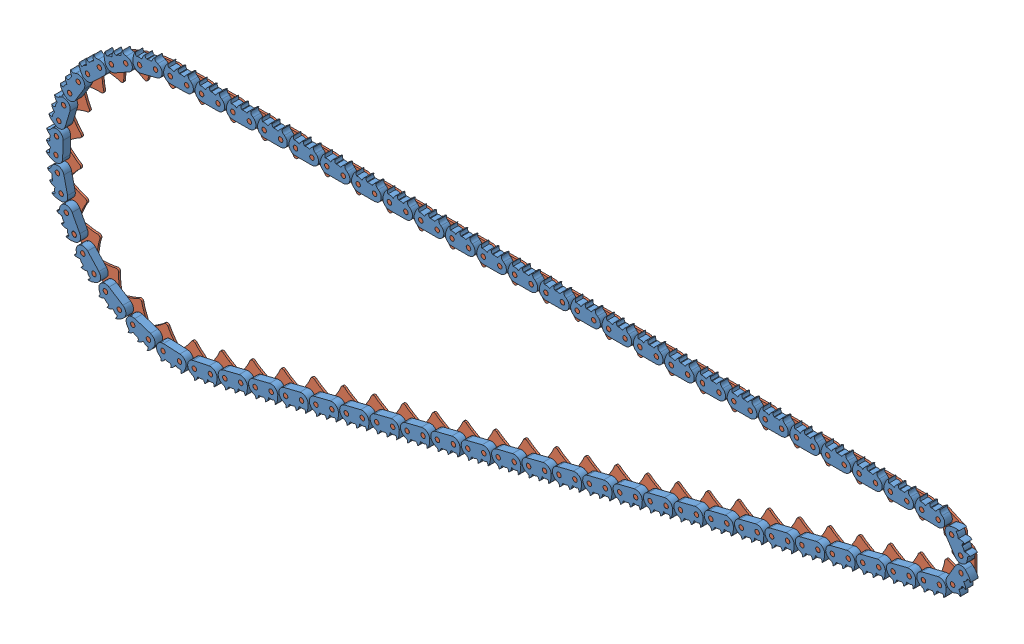
SolidWorks assembly Assem3, configuration Default. Lengths in mm.
Overall size (244.15 69.29 2.5).
128 component instances, 2 part files, 3 mates.
Components (placement in the parent):
- Teeth-4: Teeth [Default] at (-150.1835 11.9639 717.1655) x (0.465892 -0.884842 0) z (0 0 -1) size (7.83 4.36 2)
- Inner Part-4: Inner Part [Default] at (-149.4974 11.0464 714.6655) x (-0.348131 0.937446 0) z (0 0 1) size (7.41 6.1 2.5)
- Teeth-198: Teeth [Default] at (-151.9113 20.0795 717.1655) x (0.224544 -0.974464 0) z (0 0 -1) size (7.83 4.36 2)
- Teeth-199: Teeth [Default] at (-151.5087 28.3672 717.1655) x (-0.031796 -0.999494 0) z (0 0 -1) size (7.83 4.36 2)
- Teeth-200: Teeth [Default] at (-149.0024 36.2772 717.1655) x (-0.286063 -0.958211 0) z (0 0 -1) size (7.83 4.36 2)
- Teeth-201: Teeth [Default] at (-144.5589 43.2847 717.1655) x (-0.52131 -0.853367 0) z (0 0 -1) size (7.83 4.36 2)
- Teeth-202: Teeth [Default] at (-138.4738 48.9255 717.1655) x (-0.721899 -0.691999 0) z (0 0 -1) size (7.83 4.36 2)
- Teeth-203: Teeth [Default] at (-131.1508 52.827 717.1655) x (-0.874568 -0.484903 0) z (0 0 -1) size (7.83 4.36 2)
- Teeth-204: Teeth [Default] at (-123.0752 54.7323 717.1655) x (-0.969306 -0.245857 0) z (0 0 -1) size (7.83 4.36 2)
- Teeth-205: Teeth [Default] at (-114.7809 54.6665 717.1655) x (-0.999921 -0.012594 0) z (0 0 -1) size (7.83 4.36 2)
- Teeth-206: Teeth [Default] at (-106.5352 54.6348 717.1655) x (-1 0 0) z (0 0 -1) size (7.83 4.36 2)
- Teeth-207: Teeth [Default] at (-98.2897 54.6348 717.1655) x (-1 0 0) z (0 0 -1) size (7.83 4.36 2)
- Teeth-208: Teeth [Default] at (-90.0442 54.6348 717.1655) x (-1 0 0) z (0 0 -1) size (7.83 4.36 2)
- Teeth-209: Teeth [Default] at (-81.7987 54.6348 717.1655) x (-1 0 0) z (0 0 -1) size (7.83 4.36 2)
- Teeth-210: Teeth [Default] at (-73.5532 54.6348 717.1655) x (-1 0 0) z (0 0 -1) size (7.83 4.36 2)
- Teeth-211: Teeth [Default] at (-65.3077 54.6348 717.1655) x (-1 0 0) z (0 0 -1) size (7.83 4.36 2)
- Teeth-212: Teeth [Default] at (-57.0622 54.6348 717.1655) x (-1 0 0) z (0 0 -1) size (7.83 4.36 2)
- Teeth-213: Teeth [Default] at (-48.8167 54.6348 717.1655) x (-1 0 0) z (0 0 -1) size (7.83 4.36 2)
- Teeth-214: Teeth [Default] at (-40.5712 54.6348 717.1655) x (-1 0 0) z (0 0 -1) size (7.83 4.36 2)
- Teeth-215: Teeth [Default] at (-32.3257 54.6348 717.1655) x (-1 0 0) z (0 0 -1) size (7.83 4.36 2)
- Teeth-216: Teeth [Default] at (-24.0802 54.6348 717.1655) x (-1 0 0) z (0 0 -1) size (7.83 4.36 2)
- Teeth-217: Teeth [Default] at (-15.8347 54.6348 717.1655) x (-1 0 0) z (0 0 -1) size (7.83 4.36 2)
- Teeth-218: Teeth [Default] at (-7.5892 54.6348 717.1655) x (-1 0 0) z (0 0 -1) size (7.83 4.36 2)
- Teeth-219: Teeth [Default] at (0.6563 54.6348 717.1655) x (-1 0 0) z (0 0 -1) size (7.83 4.36 2)
- Teeth-220: Teeth [Default] at (8.9018 54.6348 717.1655) x (-1 0 0) z (0 0 -1) size (7.83 4.36 2)
- Teeth-221: Teeth [Default] at (17.1473 54.6348 717.1655) x (-1 0 0) z (0 0 -1) size (7.83 4.36 2)
- Teeth-222: Teeth [Default] at (25.3927 54.6348 717.1655) x (-1 0 0) z (0 0 -1) size (7.83 4.36 2)
- Teeth-223: Teeth [Default] at (33.6382 54.6348 717.1655) x (-1 0 0) z (0 0 -1) size (7.83 4.36 2)
- Teeth-224: Teeth [Default] at (41.8837 54.6348 717.1655) x (-1 0 0) z (0 0 -1) size (7.83 4.36 2)
- Teeth-225: Teeth [Default] at (50.1292 54.6348 717.1655) x (-1 0 0) z (0 0 -1) size (7.83 4.36 2)
- Teeth-226: Teeth [Default] at (58.3747 54.6348 717.1655) x (-1 0 0) z (0 0 -1) size (7.83 4.36 2)
- Teeth-227: Teeth [Default] at (66.6202 54.6348 717.1655) x (-1 0 0) z (0 0 -1) size (7.83 4.36 2)
- Teeth-228: Teeth [Default] at (74.8657 54.6348 717.1655) x (-1 0 0) z (0 0 -1) size (7.83 4.36 2)
- Teeth-229: Teeth [Default] at (83.1092 54.4672 717.1655) x (-0.999701 0.024466 0) z (0 0 -1) size (7.83 4.36 2)
- Teeth-230: Teeth [Default] at (87.9032 47.1616 717.1655) x (-0.548643 0.836057 0) z (0 0 -1) size (7.83 4.36 2)
- Teeth-231: Teeth [Default] at (83.1309 39.4575 717.1655) x (0.508767 0.860904 0) z (0 0 -1) size (7.83 4.36 2)
- Teeth-232: Teeth [Default] at (74.2952 38.1586 717.1655) x (0.97022 0.242226 0) z (0 0 -1) size (7.83 4.36 2)
- Teeth-233: Teeth [Default] at (66.2953 36.1613 717.1655) x (0.97022 0.242226 0) z (0 0 -1) size (7.83 4.36 2)
- Teeth-234: Teeth [Default] at (58.2953 34.1641 717.1655) x (0.97022 0.242226 0) z (0 0 -1) size (7.83 4.36 2)
- Teeth-235: Teeth [Default] at (50.2954 32.1668 717.1655) x (0.97022 0.242226 0) z (0 0 -1) size (7.83 4.36 2)
- Teeth-236: Teeth [Default] at (42.2954 30.1695 717.1655) x (0.97022 0.242226 0) z (0 0 -1) size (7.83 4.36 2)
- Teeth-237: Teeth [Default] at (34.2955 28.1722 717.1655) x (0.97022 0.242226 0) z (0 0 -1) size (7.83 4.36 2)
- Teeth-238: Teeth [Default] at (26.2955 26.175 717.1655) x (0.97022 0.242226 0) z (0 0 -1) size (7.83 4.36 2)
- Teeth-239: Teeth [Default] at (18.2956 24.1777 717.1655) x (0.97022 0.242226 0) z (0 0 -1) size (7.83 4.36 2)
- Teeth-240: Teeth [Default] at (10.2957 22.1804 717.1655) x (0.97022 0.242226 0) z (0 0 -1) size (7.83 4.36 2)
- Teeth-241: Teeth [Default] at (2.2957 20.1831 717.1655) x (0.97022 0.242226 0) z (0 0 -1) size (7.83 4.36 2)
- Teeth-242: Teeth [Default] at (-5.7042 18.1859 717.1655) x (0.97022 0.242226 0) z (0 0 -1) size (7.83 4.36 2)
- Teeth-243: Teeth [Default] at (-13.7042 16.1886 717.1655) x (0.97022 0.242226 0) z (0 0 -1) size (7.83 4.36 2)
- Teeth-244: Teeth [Default] at (-21.7041 14.1913 717.1655) x (0.97022 0.242226 0) z (0 0 -1) size (7.83 4.36 2)
- Teeth-245: Teeth [Default] at (-29.7041 12.194 717.1655) x (0.97022 0.242226 0) z (0 0 -1) size (7.83 4.36 2)
- Teeth-246: Teeth [Default] at (-37.704 10.1968 717.1655) x (0.97022 0.242226 0) z (0 0 -1) size (7.83 4.36 2)
- Teeth-247: Teeth [Default] at (-45.7039 8.1995 717.1655) x (0.97022 0.242226 0) z (0 0 -1) size (7.83 4.36 2)
- Teeth-248: Teeth [Default] at (-53.7039 6.2022 717.1655) x (0.97022 0.242226 0) z (0 0 -1) size (7.83 4.36 2)
- Teeth-249: Teeth [Default] at (-61.7038 4.2049 717.1655) x (0.97022 0.242226 0) z (0 0 -1) size (7.83 4.36 2)
- Teeth-250: Teeth [Default] at (-69.7038 2.2077 717.1655) x (0.97022 0.242226 0) z (0 0 -1) size (7.83 4.36 2)
- Teeth-251: Teeth [Default] at (-77.7037 0.2104 717.1655) x (0.97022 0.242226 0) z (0 0 -1) size (7.83 4.36 2)
- Teeth-252: Teeth [Default] at (-85.7037 -1.7869 717.1655) x (0.97022 0.242226 0) z (0 0 -1) size (7.83 4.36 2)
- Teeth-253: Teeth [Default] at (-93.7036 -3.7842 717.1655) x (0.97022 0.242226 0) z (0 0 -1) size (7.83 4.36 2)
- Teeth-254: Teeth [Default] at (-101.7036 -5.7814 717.1655) x (0.97022 0.242226 0) z (0 0 -1) size (7.83 4.36 2)
- Teeth-255: Teeth [Default] at (-109.7035 -7.7787 717.1655) x (0.97022 0.242226 0) z (0 0 -1) size (7.83 4.36 2)
- Teeth-256: Teeth [Default] at (-117.7659 -9.5021 717.1655) x (0.979337 0.202234 0) z (0 0 -1) size (7.83 4.36 2)
- Teeth-257: Teeth [Default] at (-126.0426 -8.9511 717.1655) x (0.998713 -0.050721 0) z (0 0 -1) size (7.83 4.36 2)
- Teeth-258: Teeth [Default] at (-133.9052 -6.3007 717.1655) x (0.952811 -0.303565 0) z (0 0 -1) size (7.83 4.36 2)
- Teeth-259: Teeth [Default] at (-140.8326 -1.7337 717.1655) x (0.843961 -0.536405 0) z (0 0 -1) size (7.83 4.36 2)
- Teeth-260: Teeth [Default] at (-146.3662 4.4489 717.1655) x (0.67927 -0.733888 0) z (0 0 -1) size (7.83 4.36 2)
- Inner Part-76: Inner Part [Default] at (-151.482 19.0172 714.6655) x (-0.097193 0.995266 0) z (0 0 1) size (7.41 6.1 2.5)
- Inner Part-77: Inner Part [Default] at (-151.365 27.2306 714.6655) x (0.160265 0.987074 0) z (0 0 1) size (7.41 6.1 2.5)
- Inner Part-78: Inner Part [Default] at (-149.1538 35.1416 714.6655) x (0.407086 0.91339 0) z (0 0 1) size (7.41 6.1 2.5)
- Inner Part-79: Inner Part [Default] at (-144.9954 42.2254 714.6655) x (0.626833 0.779154 0) z (0 0 1) size (7.41 6.1 2.5)
- Inner Part-80: Inner Part [Default] at (-139.1663 48.0129 714.6655) x (0.804934 0.593365 0) z (0 0 1) size (7.41 6.1 2.5)
- Inner Part-81: Inner Part [Default] at (-132.0533 52.1214 714.6655) x (0.929659 0.368421 0) z (0 0 1) size (7.41 6.1 2.5)
- Inner Part-82: Inner Part [Default] at (-124.1278 54.2802 714.6655) x (0.992865 0.119242 0) z (0 0 1) size (7.41 6.1 2.5)
- Inner Part-83: Inner Part [Default] at (-115.9006 54.6348 714.6655) size (7.41 6.1 2.5)
- Inner Part-84: Inner Part [Default] at (-107.6551 54.6348 714.6655) size (7.41 6.1 2.5)
- Inner Part-85: Inner Part [Default] at (-99.4096 54.6348 714.6655) size (7.41 6.1 2.5)
- Inner Part-86: Inner Part [Default] at (-91.1641 54.6348 714.6655) size (7.41 6.1 2.5)
- Inner Part-87: Inner Part [Default] at (-82.9186 54.6348 714.6655) size (7.41 6.1 2.5)
- Inner Part-88: Inner Part [Default] at (-74.6731 54.6348 714.6655) size (7.41 6.1 2.5)
- Inner Part-89: Inner Part [Default] at (-66.4276 54.6348 714.6655) size (7.41 6.1 2.5)
- Inner Part-90: Inner Part [Default] at (-58.1821 54.6348 714.6655) size (7.41 6.1 2.5)
- Inner Part-91: Inner Part [Default] at (-49.9366 54.6348 714.6655) size (7.41 6.1 2.5)
- Inner Part-92: Inner Part [Default] at (-41.6911 54.6348 714.6655) size (7.41 6.1 2.5)
- Inner Part-93: Inner Part [Default] at (-33.4456 54.6348 714.6655) size (7.41 6.1 2.5)
- Inner Part-94: Inner Part [Default] at (-25.2001 54.6348 714.6655) size (7.41 6.1 2.5)
- Inner Part-95: Inner Part [Default] at (-16.9546 54.6348 714.6655) size (7.41 6.1 2.5)
- Inner Part-96: Inner Part [Default] at (-8.7091 54.6348 714.6655) size (7.41 6.1 2.5)
- Inner Part-97: Inner Part [Default] at (-0.4636 54.6348 714.6655) size (7.41 6.1 2.5)
- Inner Part-98: Inner Part [Default] at (7.7819 54.6348 714.6655) size (7.41 6.1 2.5)
- Inner Part-99: Inner Part [Default] at (16.0274 54.6348 714.6655) size (7.41 6.1 2.5)
- Inner Part-100: Inner Part [Default] at (24.2729 54.6348 714.6655) size (7.41 6.1 2.5)
- Inner Part-101: Inner Part [Default] at (32.5184 54.6348 714.6655) size (7.41 6.1 2.5)
- Inner Part-102: Inner Part [Default] at (40.7639 54.6348 714.6655) size (7.41 6.1 2.5)
- Inner Part-103: Inner Part [Default] at (49.0094 54.6348 714.6655) size (7.41 6.1 2.5)
- Inner Part-104: Inner Part [Default] at (57.2549 54.6348 714.6655) size (7.41 6.1 2.5)
- Inner Part-105: Inner Part [Default] at (65.5004 54.6348 714.6655) size (7.41 6.1 2.5)
- Inner Part-106: Inner Part [Default] at (73.7459 54.6348 714.6655) size (7.41 6.1 2.5)
- Inner Part-107: Inner Part [Default] at (81.8614 53.9433 714.6655) x (0.907813 -0.419375 0) z (0 0 1) size (7.41 6.1 2.5)
- Inner Part-108: Inner Part [Default] at (86.556 47.8695 714.6655) x (0.023721 -0.999719 0) z (0 0 1) size (7.41 6.1 2.5)
- Inner Part-109: Inner Part [Default] at (83.1725 40.979 714.6655) x (-0.887089 -0.461599 0) z (0 0 1) size (7.41 6.1 2.5)
- Inner Part-110: Inner Part [Default] at (75.3817 38.4299 714.6655) x (-0.97022 -0.242226 0) z (0 0 1) size (7.41 6.1 2.5)
- Inner Part-111: Inner Part [Default] at (67.3818 36.4326 714.6655) x (-0.97022 -0.242226 0) z (0 0 1) size (7.41 6.1 2.5)
- Inner Part-112: Inner Part [Default] at (59.3818 34.4353 714.6655) x (-0.97022 -0.242226 0) z (0 0 1) size (7.41 6.1 2.5)
- Inner Part-113: Inner Part [Default] at (51.3819 32.438 714.6655) x (-0.97022 -0.242226 0) z (0 0 1) size (7.41 6.1 2.5)
- Inner Part-114: Inner Part [Default] at (43.382 30.4408 714.6655) x (-0.97022 -0.242226 0) z (0 0 1) size (7.41 6.1 2.5)
- Inner Part-115: Inner Part [Default] at (35.382 28.4435 714.6655) x (-0.97022 -0.242226 0) z (0 0 1) size (7.41 6.1 2.5)
- Inner Part-116: Inner Part [Default] at (27.3821 26.4462 714.6655) x (-0.97022 -0.242226 0) z (0 0 1) size (7.41 6.1 2.5)
- Inner Part-117: Inner Part [Default] at (19.3821 24.4489 714.6655) x (-0.97022 -0.242226 0) z (0 0 1) size (7.41 6.1 2.5)
- Inner Part-118: Inner Part [Default] at (11.3822 22.4517 714.6655) x (-0.97022 -0.242226 0) z (0 0 1) size (7.41 6.1 2.5)
- Inner Part-119: Inner Part [Default] at (3.3822 20.4544 714.6655) x (-0.97022 -0.242226 0) z (0 0 1) size (7.41 6.1 2.5)
- Inner Part-120: Inner Part [Default] at (-4.6177 18.4571 714.6655) x (-0.97022 -0.242226 0) z (0 0 1) size (7.41 6.1 2.5)
- Inner Part-121: Inner Part [Default] at (-12.6177 16.4599 714.6655) x (-0.97022 -0.242226 0) z (0 0 1) size (7.41 6.1 2.5)
- Inner Part-122: Inner Part [Default] at (-20.6176 14.4626 714.6655) x (-0.97022 -0.242226 0) z (0 0 1) size (7.41 6.1 2.5)
- Inner Part-123: Inner Part [Default] at (-28.6175 12.4653 714.6655) x (-0.97022 -0.242226 0) z (0 0 1) size (7.41 6.1 2.5)
- Inner Part-124: Inner Part [Default] at (-36.6175 10.468 714.6655) x (-0.97022 -0.242226 0) z (0 0 1) size (7.41 6.1 2.5)
- Inner Part-125: Inner Part [Default] at (-44.6174 8.4708 714.6655) x (-0.97022 -0.242226 0) z (0 0 1) size (7.41 6.1 2.5)
- Inner Part-126: Inner Part [Default] at (-52.6174 6.4735 714.6655) x (-0.97022 -0.242226 0) z (0 0 1) size (7.41 6.1 2.5)
- Inner Part-127: Inner Part [Default] at (-60.6173 4.4762 714.6655) x (-0.97022 -0.242226 0) z (0 0 1) size (7.41 6.1 2.5)
- Inner Part-128: Inner Part [Default] at (-68.6173 2.4789 714.6655) x (-0.97022 -0.242226 0) z (0 0 1) size (7.41 6.1 2.5)
- Inner Part-129: Inner Part [Default] at (-76.6172 0.4817 714.6655) x (-0.97022 -0.242226 0) z (0 0 1) size (7.41 6.1 2.5)
- Inner Part-130: Inner Part [Default] at (-84.6171 -1.5156 714.6655) x (-0.97022 -0.242226 0) z (0 0 1) size (7.41 6.1 2.5)
- Inner Part-131: Inner Part [Default] at (-92.6171 -3.5129 714.6655) x (-0.97022 -0.242226 0) z (0 0 1) size (7.41 6.1 2.5)
- Inner Part-132: Inner Part [Default] at (-100.617 -5.5102 714.6655) x (-0.97022 -0.242226 0) z (0 0 1) size (7.41 6.1 2.5)
- Inner Part-133: Inner Part [Default] at (-108.617 -7.5074 714.6655) x (-0.97022 -0.242226 0) z (0 0 1) size (7.41 6.1 2.5)
- Inner Part-134: Inner Part [Default] at (-116.6938 -9.1022 714.6655) x (-0.996951 -0.07803 0) z (0 0 1) size (7.41 6.1 2.5)
- Inner Part-135: Inner Part [Default] at (-124.9035 -8.8293 714.6655) x (-0.983918 0.178622 0) z (0 0 1) size (7.41 6.1 2.5)
- Inner Part-136: Inner Part [Default] at (-132.7727 -6.4732 714.6655) x (-0.905902 0.423487 0) z (0 0 1) size (7.41 6.1 2.5)
- Inner Part-137: Inner Part [Default] at (-139.7814 -2.1891 714.6655) x (-0.768001 0.640448 0) z (0 0 1) size (7.41 6.1 2.5)
- Inner Part-138: Inner Part [Default] at (-145.4659 3.7405 714.6655) x (-0.579229 0.815165 0) z (0 0 1) size (7.41 6.1 2.5)
Mates (geometry in assembly coordinates):
- Concentric5: concentric: cylinder of Teeth-4 through (-149.0114 9.7378 717.1655) axis (0 0 -1) radius 0.6; cylinder of Inner Part-4 through (-149.0114 9.7378 714.6655) axis (0 0 1) radius 0.6
- Parallel3: parallel: plane of Teeth-198 through (-151.9113 20.0795 716.1655) normal (0 0 1); plane of assembly through (0 0 0) normal (0 0 1)
- Parallel4: parallel: plane of Teeth-199 through (-151.5087 28.3672 716.1655) normal (0 0 1); plane of assembly through (0 0 0) normal (0 0 1)
